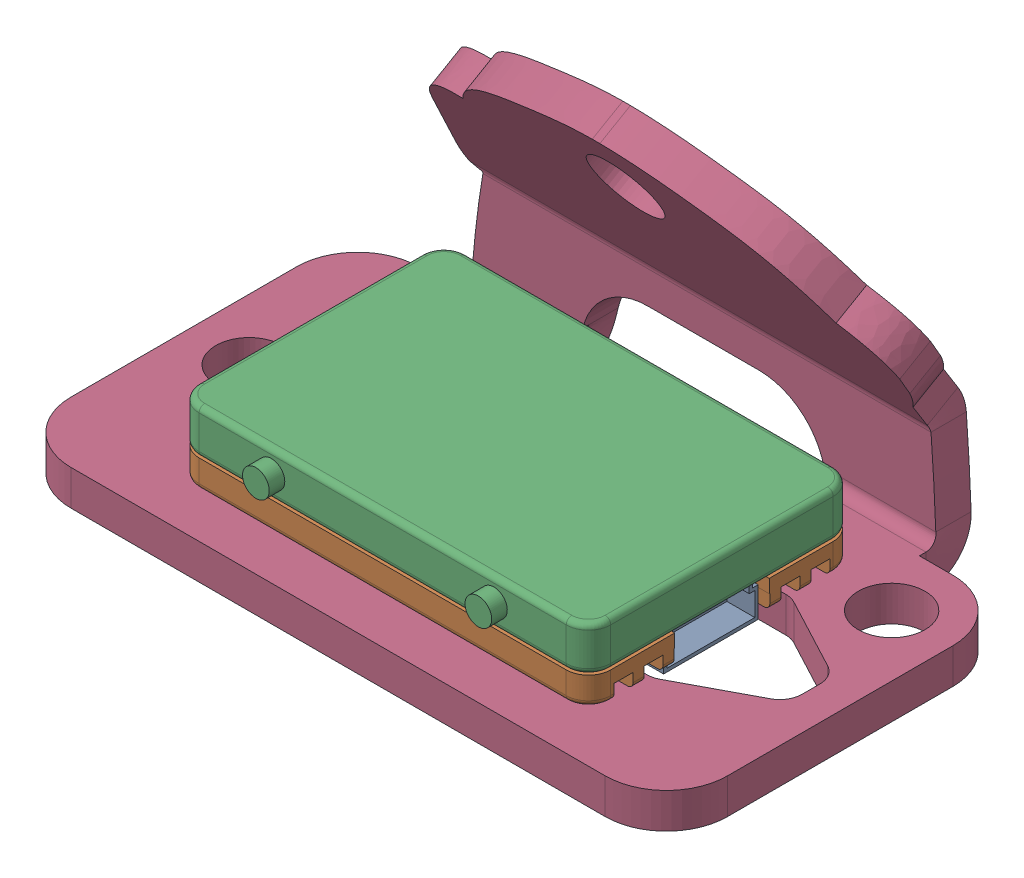
SolidWorks assembly vtxmount01, configuration Default. Lengths in mm.
Overall size (59 30.92 36.03).
2 component instances, 2 part files, 1 mates.
Components (placement in the parent):
- RushTankSoloModel-1: RushTankSoloModel [Default] at (0 8.1283 0) x (-1 0 0) z (0 -1 0) size (37 25.4 7.7)
- mount-1: mount [Default] at (0 1.6283 0) x (1 0 0) z (0 1 0) size (59 36.03 30.92)
Mates (geometry in assembly coordinates):
- Coincident5: coincident anti-aligned: plane of RushTankSoloModel-1 through (16.5 1.6283 -10) normal (0 -1 0); plane of mount^vtxmount01-1 through (0 1.6283 0) normal (0 1 0)
